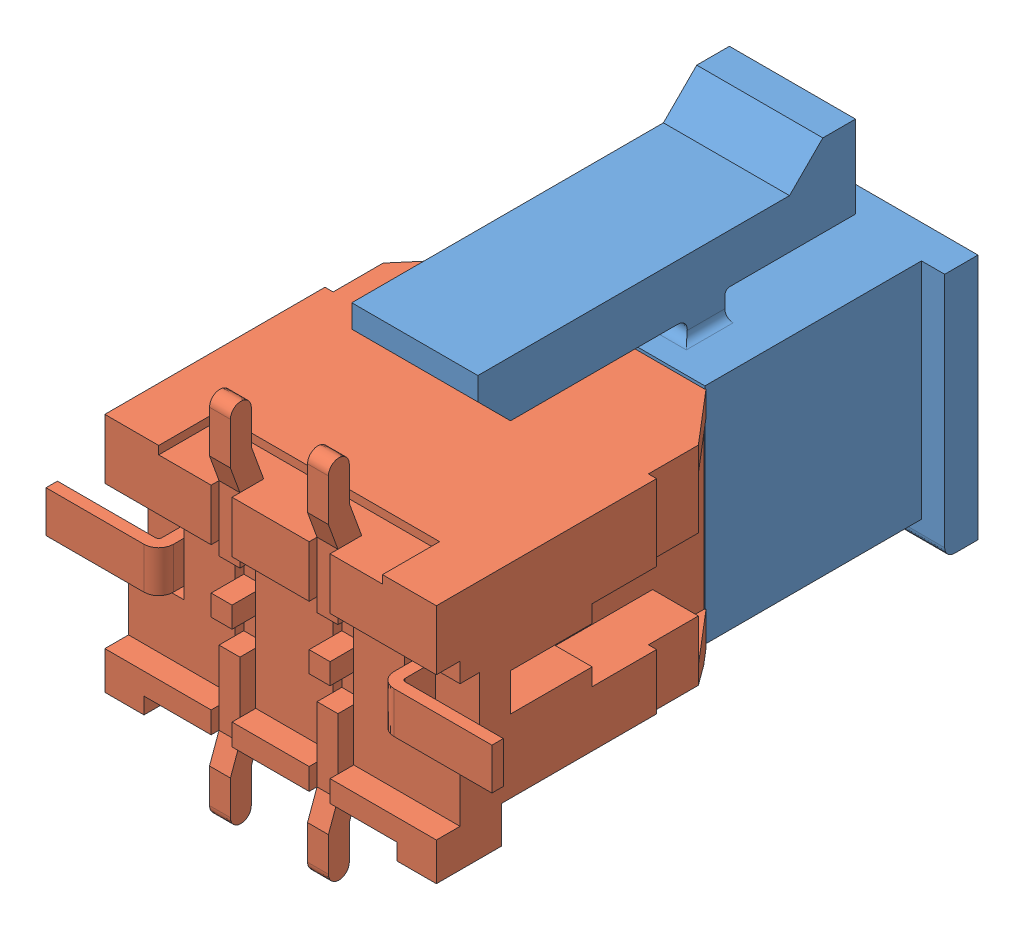
SolidWorks assembly Assem1, configuration Default. Lengths in mm.
Overall size (13.65 12.41 17.55).
2 component instances, 2 part files, 0 mates.
Components (placement in the parent):
- 430250400-1: 430250400 [Default] at (5.9582 9.087 5.2796) x (1 0 0) z (0 -1 0) size (8.27 14 10.83)
- 430450418-1: 430450418 [Default] at (5.9325 8.9881 13.819) x (-1 0 0) z (0 0 -1) size (13.65 11.2 9.96)
